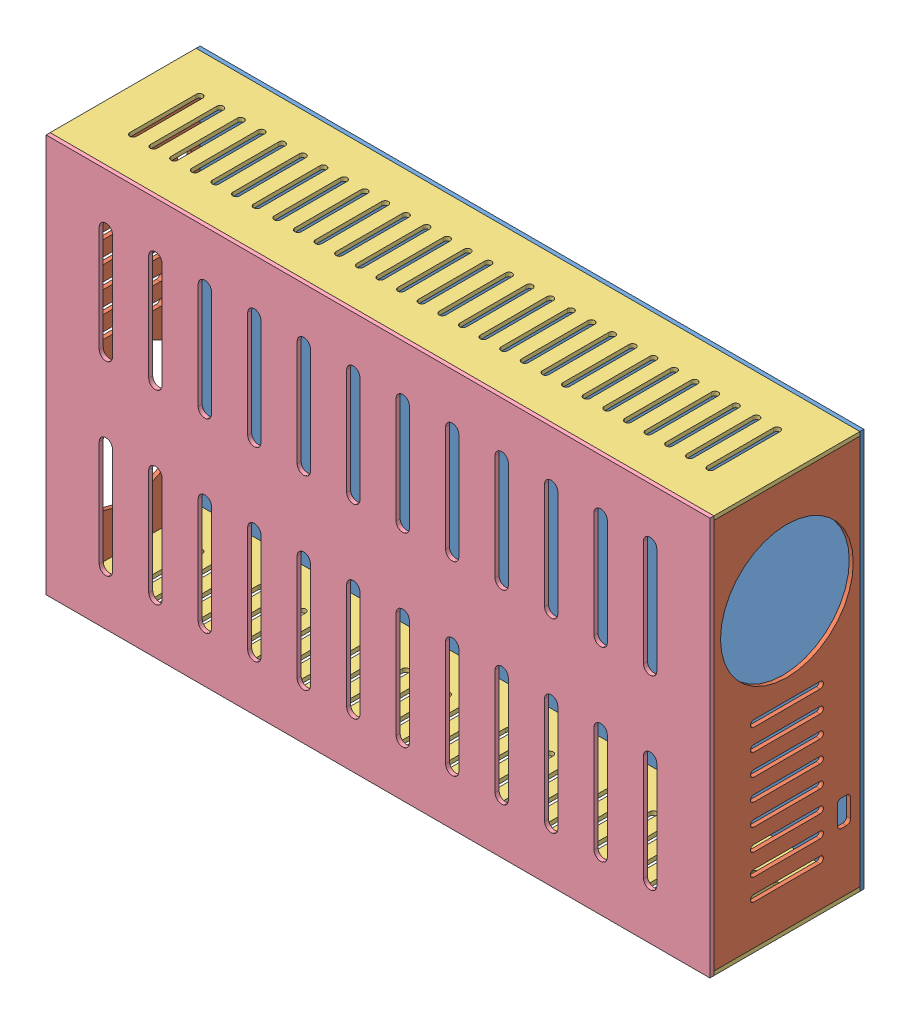
SolidWorks assembly drivesbox, configuration Varsayılan. Lengths in mm.
Overall size (500 300 116).
6 component instances, 4 part files, 15 mates.
Components (placement in the parent):
- 50x30-1: 50x30 [Varsayılan] at (-222.2061 117.1171 498.5) size (500 300 3)
- 11x294-1: 11x294 [Varsayılan] at (-219.2061 114.1171 611.5) x (-1 0 0) z (0 1 0) size (3 110 294)
- 11x294-2: 11x294 [Varsayılan] at (274.7939 -179.8829 611.5) x (1 0 0) z (0 -1 0) size (3 110 294)
- 11x50-1: 11x50 [Varsayılan] at (-222.2061 -182.8829 501.5) size (500 3 110)
- 11x50-2: 11x50 [Varsayılan] at (-222.2061 114.1171 501.5) size (500 3 110)
- ust50x30-1: ust50x30 [Varsayılan] at (-222.2061 117.1171 611.5) size (500 300 3)
Mates (geometry in assembly coordinates):
- Çakışık1: coincident aligned: plane of 50x30-1 through (-222.2061 -182.8829 501.5) normal (0 -1 0); plane of 11x50-1 through (-222.2061 -182.8829 501.5) normal (0 -1 0)
- Çakışık2: coincident aligned: plane of 50x30-1 through (-222.2061 117.1171 501.5) normal (-1 0 0); plane of 11x50-1 through (-222.2061 -179.8829 501.5) normal (-1 0 0)
- Çakışık4: coincident anti-aligned: plane of 50x30-1 through (-222.2061 117.1171 501.5) normal (0 0 1); plane of 11x50-1 through (-222.2061 -179.8829 501.5) normal (0 0 -1)
- Çakışık5: coincident aligned: plane of 11x294-1 through (-222.2061 114.1171 611.5) normal (-1 0 0); plane of 11x50-1 through (-222.2061 -179.8829 501.5) normal (-1 0 0)
- Çakışık6: coincident anti-aligned: plane of 11x294-1 through (-222.2061 -179.8829 611.5) normal (0 -1 0); plane of 11x50-1 through (-222.2061 -179.8829 501.5) normal (0 1 0)
- Çakışık7: coincident aligned: plane of 11x294-1 through (-222.2061 114.1171 611.5) normal (0 0 1); plane of 11x50-1 through (-222.2061 -179.8829 611.5) normal (0 0 1)
- Çakışık8: coincident anti-aligned: plane of 11x294-1 through (-222.2061 114.1171 611.5) normal (0 1 0); plane of 11x50-2 through (-222.2061 114.1171 501.5) normal (0 -1 0)
- Çakışık9: coincident aligned: plane of 11x294-1 through (-222.2061 114.1171 611.5) normal (-1 0 0); plane of 11x50-2 through (-222.2061 117.1171 501.5) normal (-1 0 0)
- Çakışık10: coincident anti-aligned: plane of 50x30-1 through (-222.2061 117.1171 501.5) normal (0 0 1); plane of 11x50-2 through (-222.2061 117.1171 501.5) normal (0 0 -1)
- Çakışık11: coincident aligned: plane of 50x30-1 through (277.7939 117.1171 501.5) normal (1 0 0); plane of 11x294-2 through (277.7939 -179.8829 611.5) normal (1 0 0)
- Çakışık12: coincident aligned: plane of 11x294-2 through (277.7939 -179.8829 611.5) normal (0 0 1); plane of 11x50-1 through (-222.2061 -179.8829 611.5) normal (0 0 1)
- Çakışık13: coincident anti-aligned: plane of 11x294-2 through (277.7939 -179.8829 611.5) normal (0 -1 0); plane of 11x50-1 through (-222.2061 -179.8829 501.5) normal (0 1 0)
- Çakışık15: coincident: plane of 11x294-1 through (-222.2061 114.1171 611.5) normal (-1 0 0); plane of ust50x30-1 through (-222.2061 117.1171 614.5) normal (-1 0 0)
- Çakışık16: coincident: plane of 11x50-1 through (-222.2061 -182.8829 501.5) normal (0 -1 0); plane of ust50x30-1 through (-222.2061 -182.8829 614.5) normal (0 -1 0)
- Çakışık18: coincident anti-aligned: plane of 11x50-1 through (-222.2061 -179.8829 611.5) normal (0 0 1); plane of ust50x30-1 through (-222.2061 117.1171 611.5) normal (0 0 -1)
